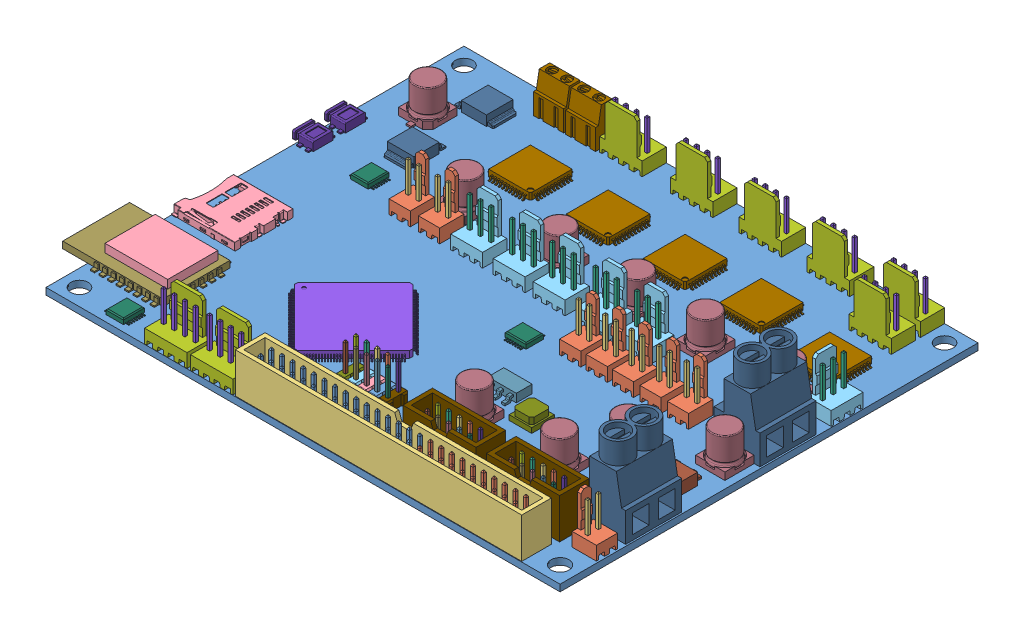
SolidWorks assembly Duet WIfi Rev 4, configuration Default. Lengths in mm.
Overall size (129 22.52 100).
221 component instances, 40 part files, 0 mates.
Components (placement in the parent):
- Main PCB v56-1: Main PCB v56 [Default] at origin size (123 1.6 100)
- Molex PCB 2 pin v2-1: Molex PCB 2 pin v2 [Default] at (-35.5344 13.1082 -6.1109) x (1 0 0) z (0 1 0) size (5.08 5.79 14.92)
  - BASE9710016_1-1: BASE9710016_1 [Default] at (2.54 2.895 -8.22) size (5.08 5.79 11.5)
  - PINO9710016_1-1: PINO9710016_1 [Default] at (1.27 3.325 -0.72) size (0.65 0.65 14.2)
  - PINO9710016_1-2: PINO9710016_1 [Default] at (3.81 3.325 -0.72) size (0.65 0.65 14.2)
- Molex PCB 2 pin v2_1-1: Molex PCB 2 pin v2_1 [Default] at (-28.4802 13.1082 -6.1109) x (1 0 0) z (0 1 0) size (5.08 5.79 14.92)
  - BASE9710016_1-1: BASE9710016_1 [Default] at (2.54 2.895 -8.22) size (5.08 5.79 11.5)
  - PINO9710016_1-1: PINO9710016_1 [Default] at (1.27 3.325 -0.72) size (0.65 0.65 14.2)
  - PINO9710016_1-2: PINO9710016_1 [Default] at (3.81 3.325 -0.72) size (0.65 0.65 14.2)
- microSD1 v4-1: microSD1 v4 [Default] at (-62.4462 1.5952 12.9853) x (0 0 1) z (-1 0 0) size (14.1 1.88 15.2)
- Molex PCB 2 pin v2_2-1: Molex PCB 2 pin v2_2 [Default] at (13.9179 13.1082 2.5426) x (1 0 0) z (0 1 0) size (5.08 5.79 14.92)
  - BASE9710016_1-1: BASE9710016_1 [Default] at (2.54 2.895 -8.22) size (5.08 5.79 11.5)
  - PINO9710016_1-1: PINO9710016_1 [Default] at (1.27 3.325 -0.72) size (0.65 0.65 14.2)
  - PINO9710016_1-2: PINO9710016_1 [Default] at (3.81 3.325 -0.72) size (0.65 0.65 14.2)
- Molex PCB 2 pin v2_3-1: Molex PCB 2 pin v2_3 [Default] at (20.2886 13.1082 2.5426) x (1 0 0) z (0 1 0) size (5.08 5.79 14.92)
  - BASE9710016_1-1: BASE9710016_1 [Default] at (2.54 2.895 -8.22) size (5.08 5.79 11.5)
  - PINO9710016_1-1: PINO9710016_1 [Default] at (1.27 3.325 -0.72) size (0.65 0.65 14.2)
  - PINO9710016_1-2: PINO9710016_1 [Default] at (3.81 3.325 -0.72) size (0.65 0.65 14.2)
- Molex PCB 2 pin v2_4-1: Molex PCB 2 pin v2_4 [Default] at (26.5531 13.1082 2.5426) x (1 0 0) z (0 1 0) size (5.08 5.79 14.92)
  - BASE9710016_1-1: BASE9710016_1 [Default] at (2.54 2.895 -8.22) size (5.08 5.79 11.5)
  - PINO9710016_1-1: PINO9710016_1 [Default] at (1.27 3.325 -0.72) size (0.65 0.65 14.2)
  - PINO9710016_1-2: PINO9710016_1 [Default] at (3.81 3.325 -0.72) size (0.65 0.65 14.2)
- Molex PCB 2 pin v2_5-1: Molex PCB 2 pin v2_5 [Default] at (33.1361 13.1082 2.5426) x (1 0 0) z (0 1 0) size (5.08 5.79 14.92)
  - BASE9710016_1-1: BASE9710016_1 [Default] at (2.54 2.895 -8.22) size (5.08 5.79 11.5)
  - PINO9710016_1-1: PINO9710016_1 [Default] at (1.27 3.325 -0.72) size (0.65 0.65 14.2)
  - PINO9710016_1-2: PINO9710016_1 [Default] at (3.81 3.325 -0.72) size (0.65 0.65 14.2)
- Molex PCB 2 pin v2_6-1: Molex PCB 2 pin v2_6 [Default] at (39.7191 13.1082 2.5426) x (1 0 0) z (0 1 0) size (5.08 5.79 14.92)
  - BASE9710016_1-1: BASE9710016_1 [Default] at (2.54 2.895 -8.22) size (5.08 5.79 11.5)
  - PINO9710016_1-1: PINO9710016_1 [Default] at (1.27 3.325 -0.72) size (0.65 0.65 14.2)
  - PINO9710016_1-2: PINO9710016_1 [Default] at (3.81 3.325 -0.72) size (0.65 0.65 14.2)
- Molex PCB 3 pin v2 v6-1: Molex PCB 3 pin v2 v6 [Default] at (-20.7566 13.2093 -6.0914) x (1 0 0) z (0 1 0) size (7.62 5.79 14.92)
  - BASE9710016_2-1: BASE9710016_2 [Default] at (2.54 2.895 -8.22) size (7.62 5.79 11.5)
  - PINO9710016_2-1: PINO9710016_2 [Default] at (1.27 3.325 -0.72) size (0.65 0.65 14.2)
  - PINO9710016_2-2: PINO9710016_2 [Default] at (3.81 3.325 -0.72) size (0.65 0.65 14.2)
  - PINO9710016_2-3: PINO9710016_2 [Default] at (6.35 3.325 -0.72) size (0.65 0.65 14.2)
- Molex PCB 3 pin v2 v6_1-1: Molex PCB 3 pin v2 v6_1 [Default] at (-10.5889 13.2093 -6.0914) x (1 0 0) z (0 1 0) size (7.62 5.79 14.92)
  - BASE9710016_2-1: BASE9710016_2 [Default] at (2.54 2.895 -8.22) size (7.62 5.79 11.5)
  - PINO9710016_2-1: PINO9710016_2 [Default] at (1.27 3.325 -0.72) size (0.65 0.65 14.2)
  - PINO9710016_2-2: PINO9710016_2 [Default] at (3.81 3.325 -0.72) size (0.65 0.65 14.2)
  - PINO9710016_2-3: PINO9710016_2 [Default] at (6.35 3.325 -0.72) size (0.65 0.65 14.2)
- Molex PCB 3 pin v2 v6_2-1: Molex PCB 3 pin v2 v6_2 [Default] at (-1.0164 13.2093 -6.0914) x (1 0 0) z (0 1 0) size (7.62 5.79 14.92)
  - BASE9710016_2-1: BASE9710016_2 [Default] at (2.54 2.895 -8.22) size (7.62 5.79 11.5)
  - PINO9710016_2-1: PINO9710016_2 [Default] at (1.27 3.325 -0.72) size (0.65 0.65 14.2)
  - PINO9710016_2-2: PINO9710016_2 [Default] at (3.81 3.325 -0.72) size (0.65 0.65 14.2)
  - PINO9710016_2-3: PINO9710016_2 [Default] at (6.35 3.325 -0.72) size (0.65 0.65 14.2)
- Molex PCB 3 pin v2 v6_3-1: Molex PCB 3 pin v2 v6_3 [Default] at (9.3326 13.2093 -6.0914) x (1 0 0) z (0 1 0) size (7.62 5.79 14.92)
  - BASE9710016_2-1: BASE9710016_2 [Default] at (2.54 2.895 -8.22) size (7.62 5.79 11.5)
  - PINO9710016_2-1: PINO9710016_2 [Default] at (1.27 3.325 -0.72) size (0.65 0.65 14.2)
  - PINO9710016_2-2: PINO9710016_2 [Default] at (3.81 3.325 -0.72) size (0.65 0.65 14.2)
  - PINO9710016_2-3: PINO9710016_2 [Default] at (6.35 3.325 -0.72) size (0.65 0.65 14.2)
- Molex PCB 3 pin v2 v6_4-1: Molex PCB 3 pin v2 v6_4 [Default] at (19.2437 13.2093 -6.0914) x (1 0 0) z (0 1 0) size (7.62 5.79 14.92)
  - BASE9710016_2-1: BASE9710016_2 [Default] at (2.54 2.895 -8.22) size (7.62 5.79 11.5)
  - PINO9710016_2-1: PINO9710016_2 [Default] at (1.27 3.325 -0.72) size (0.65 0.65 14.2)
  - PINO9710016_2-2: PINO9710016_2 [Default] at (3.81 3.325 -0.72) size (0.65 0.65 14.2)
  - PINO9710016_2-3: PINO9710016_2 [Default] at (6.35 3.325 -0.72) size (0.65 0.65 14.2)
- Molex PCB 4 pin v3-1: Molex PCB 4 pin v3 [Default] at (-37.9459 13.1477 49.9775) x (1 0 0) z (0 1 0) size (10.16 5.79 14.92)
  - BASE9710016-1: BASE9710016 [Default] at (2.54 2.895 -8.22) size (10.16 5.79 11.5)
  - PINO9710016-1: PINO9710016 [Default] at (1.27 3.325 -0.72) size (0.65 0.65 14.2)
  - PINO9710016-2: PINO9710016 [Default] at (3.81 3.325 -0.72) size (0.65 0.65 14.2)
  - PINO9710016-3: PINO9710016 [Default] at (6.35 3.325 -0.72) size (0.65 0.65 14.2)
  - PINO9710016-4: PINO9710016 [Default] at (8.89 3.325 -0.72) size (0.65 0.65 14.2)
- Molex PCB 4 pin v3_1-1: Molex PCB 4 pin v3_1 [Default] at (-26.9715 13.1477 49.9775) x (1 0 0) z (0 1 0) size (10.16 5.79 14.92)
  - BASE9710016-1: BASE9710016 [Default] at (2.54 2.895 -8.22) size (10.16 5.79 11.5)
  - PINO9710016-1: PINO9710016 [Default] at (1.27 3.325 -0.72) size (0.65 0.65 14.2)
  - PINO9710016-2: PINO9710016 [Default] at (3.81 3.325 -0.72) size (0.65 0.65 14.2)
  - PINO9710016-3: PINO9710016 [Default] at (6.35 3.325 -0.72) size (0.65 0.65 14.2)
  - PINO9710016-4: PINO9710016 [Default] at (8.89 3.325 -0.72) size (0.65 0.65 14.2)
- Molex PCB 4 pin v3_2-1: Molex PCB 4 pin v3_2 [Default] at (-13.0474 13.1477 -49.9787) x (-1 0 0) z (0 1 0) size (10.16 5.79 14.92)
  - BASE9710016-1: BASE9710016 [Default] at (2.54 2.895 -8.22) size (10.16 5.79 11.5)
  - PINO9710016-1: PINO9710016 [Default] at (1.27 3.325 -0.72) size (0.65 0.65 14.2)
  - PINO9710016-2: PINO9710016 [Default] at (3.81 3.325 -0.72) size (0.65 0.65 14.2)
  - PINO9710016-3: PINO9710016 [Default] at (6.35 3.325 -0.72) size (0.65 0.65 14.2)
  - PINO9710016-4: PINO9710016 [Default] at (8.89 3.325 -0.72) size (0.65 0.65 14.2)
- Molex PCB 4 pin v3_3-1: Molex PCB 4 pin v3_3 [Default] at (3.87 13.1477 -49.9787) x (-1 0 0) z (0 1 0) size (10.16 5.79 14.92)
  - BASE9710016-1: BASE9710016 [Default] at (2.54 2.895 -8.22) size (10.16 5.79 11.5)
  - PINO9710016-1: PINO9710016 [Default] at (1.27 3.325 -0.72) size (0.65 0.65 14.2)
  - PINO9710016-2: PINO9710016 [Default] at (3.81 3.325 -0.72) size (0.65 0.65 14.2)
  - PINO9710016-3: PINO9710016 [Default] at (6.35 3.325 -0.72) size (0.65 0.65 14.2)
  - PINO9710016-4: PINO9710016 [Default] at (8.89 3.325 -0.72) size (0.65 0.65 14.2)
- Molex PCB 4 pin v3_4-1: Molex PCB 4 pin v3_4 [Default] at (20.2963 13.1477 -49.9787) x (-1 0 0) z (0 1 0) size (10.16 5.79 14.92)
  - BASE9710016-1: BASE9710016 [Default] at (2.54 2.895 -8.22) size (10.16 5.79 11.5)
  - PINO9710016-1: PINO9710016 [Default] at (1.27 3.325 -0.72) size (0.65 0.65 14.2)
  - PINO9710016-2: PINO9710016 [Default] at (3.81 3.325 -0.72) size (0.65 0.65 14.2)
  - PINO9710016-3: PINO9710016 [Default] at (6.35 3.325 -0.72) size (0.65 0.65 14.2)
  - PINO9710016-4: PINO9710016 [Default] at (8.89 3.325 -0.72) size (0.65 0.65 14.2)
- Molex PCB 4 pin v3_5-1: Molex PCB 4 pin v3_5 [Default] at (36.6134 13.1477 -49.9787) x (-1 0 0) z (0 1 0) size (10.16 5.79 14.92)
  - BASE9710016-1: BASE9710016 [Default] at (2.54 2.895 -8.22) size (10.16 5.79 11.5)
  - PINO9710016-1: PINO9710016 [Default] at (1.27 3.325 -0.72) size (0.65 0.65 14.2)
  - PINO9710016-2: PINO9710016 [Default] at (3.81 3.325 -0.72) size (0.65 0.65 14.2)
  - PINO9710016-3: PINO9710016 [Default] at (6.35 3.325 -0.72) size (0.65 0.65 14.2)
  - PINO9710016-4: PINO9710016 [Default] at (8.89 3.325 -0.72) size (0.65 0.65 14.2)
- Molex PCB 4 pin v3_6-1: Molex PCB 4 pin v3_6 [Default] at (53.5582 13.1477 -49.9787) x (-1 0 0) z (0 1 0) size (10.16 5.79 14.92)
  - BASE9710016-1: BASE9710016 [Default] at (2.54 2.895 -8.22) size (10.16 5.79 11.5)
  - PINO9710016-1: PINO9710016 [Default] at (1.27 3.325 -0.72) size (0.65 0.65 14.2)
  - PINO9710016-2: PINO9710016 [Default] at (3.81 3.325 -0.72) size (0.65 0.65 14.2)
  - PINO9710016-3: PINO9710016 [Default] at (6.35 3.325 -0.72) size (0.65 0.65 14.2)
  - PINO9710016-4: PINO9710016 [Default] at (8.89 3.325 -0.72) size (0.65 0.65 14.2)
- Molex PCB 4 pin v3_7-1: Molex PCB 4 pin v3_7 [Default] at (53.5582 13.1477 -42.9934) x (-1 0 0) z (0 1 0) size (10.16 5.79 14.92)
  - BASE9710016-1: BASE9710016 [Default] at (2.54 2.895 -8.22) size (10.16 5.79 11.5)
  - PINO9710016-1: PINO9710016 [Default] at (1.27 3.325 -0.72) size (0.65 0.65 14.2)
  - PINO9710016-2: PINO9710016 [Default] at (3.81 3.325 -0.72) size (0.65 0.65 14.2)
  - PINO9710016-3: PINO9710016 [Default] at (6.35 3.325 -0.72) size (0.65 0.65 14.2)
  - PINO9710016-4: PINO9710016 [Default] at (8.89 3.325 -0.72) size (0.65 0.65 14.2)
- 2 pole terminal block v7-1: 2 pole terminal block v7 [Default] at (-27.4689 1.6269 -46.8568) x (-1 0 0) z (0 0 -1) size (7.2 9 6)
- 2 pole terminal block v7-2: 2 pole terminal block v7 [Default] at (-35.1283 1.6572 -46.8568) x (-1 0 0) z (0 0 -1) size (7.2 9 6)
- 2 pole terminal block large v7-1: 2 pole terminal block large v7 [Default] at (55.6089 1.6 -4.9109) x (0 0 -1) z (1 0 0) size (13.4 19.1 11)
- 2 pole terminal block large v7-2: 2 pole terminal block large v7 [Default] at (55.6089 1.6 27.2029) x (0 0 -1) z (1 0 0) size (13.4 19.1 11)
- Molex PCB 2 pin v2_7-1: Molex PCB 2 pin v2_7 [Default] at (61.0807 13.1082 40.8944) x (0 0 -1) z (0 1 0) size (5.08 5.79 14.92)
  - BASE9710016_1-1: BASE9710016_1 [Default] at (2.54 2.895 -8.22) size (5.08 5.79 11.5)
  - PINO9710016_1-1: PINO9710016_1 [Default] at (1.27 3.325 -0.72) size (0.65 0.65 14.2)
  - PINO9710016_1-2: PINO9710016_1 [Default] at (3.81 3.325 -0.72) size (0.65 0.65 14.2)
- Molex PCB 3 pin v2 v6_5-1: Molex PCB 3 pin v2 v6_5 [Default] at (61.3453 13.2093 -15.0112) x (0 0 -1) z (0 1 0) size (7.62 5.79 14.92)
  - BASE9710016_2-1: BASE9710016_2 [Default] at (2.54 2.895 -8.22) size (7.62 5.79 11.5)
  - PINO9710016_2-1: PINO9710016_2 [Default] at (1.27 3.325 -0.72) size (0.65 0.65 14.2)
  - PINO9710016_2-2: PINO9710016_2 [Default] at (3.81 3.325 -0.72) size (0.65 0.65 14.2)
  - PINO9710016_2-3: PINO9710016_2 [Default] at (6.35 3.325 -0.72) size (0.65 0.65 14.2)
- Pin Header 2x5 TH Pitch 2.54mm v4-1: Pin Header 2x5 TH Pitch 2.54mm v4 [Default] at (-5.2178 1.6022 33.3605) x (1 0 0) z (0 1 0) size (12.7 5.08 12.7)
  - Component1_5-1: Component1_5 [Default] at origin size (0.63 0.63 12.7)
  - Component2-1: Component2 [Default] at origin size (0.63 0.63 12.7)
  - Component3-1: Component3 [Default] at origin size (0.63 0.63 12.7)
  - Component4-1: Component4 [Default] at origin size (0.63 0.63 12.7)
  - Component5-1: Component5 [Default] at origin size (0.63 0.63 12.7)
  - Component6-1: Component6 [Default] at origin size (2.54 5.08 2.8)
  - Component7-1: Component7 [Default] at origin size (0.63 0.63 12.7)
  - Component8-1: Component8 [Default] at origin size (2.54 5.08 2.8)
  - Component9-1: Component9 [Default] at origin size (2.54 5.08 2.8)
  - Component10-1: Component10 [Default] at origin size (0.63 0.63 12.7)
  - Component11-1: Component11 [Default] at origin size (0.63 0.63 12.7)
  - Component12-1: Component12 [Default] at origin size (2.54 5.08 2.8)
  - Component13-1: Component13 [Default] at origin size (2.54 5.08 2.8)
  - Component14-1: Component14 [Default] at origin size (0.63 0.63 12.7)
  - Component15-1: Component15 [Default] at origin size (0.63 0.63 12.7)
- Arm cortex Sam4E8E v6 v7-1: Arm cortex Sam4E8E v6 v7 [Default] at (-17.0062 1.6459 20.877) x (0.707107 0 0.707107) z (-0.707107 0 0.707107) size (22 1.6 22)
  - Component1-1: Component1 [Default] at origin size (22 1.6 22)
- Trinamic 2660-PA v3-1: Trinamic 2660-PA v3 [Default] at (-26.4607 1.6002 -30.8647) x (-1 0 -0.000001) z (0.000001 0 -1) size (12 1.6 12)
  - Component1_1-1: Component1_1 [Default] at origin size (12 1.6 12)
- Trinamic 2660-PA v3-2: Trinamic 2660-PA v3 [Default] at (-7.8607 1.6002 -30.8647) x (-1 0 -0.000001) z (0.000001 0 -1) size (12 1.6 12)
  - Component1_1-1: Component1_1 [Default] at origin size (12 1.6 12)
- Trinamic 2660-PA v3-3: Trinamic 2660-PA v3 [Default] at (10.5393 1.6002 -30.8647) x (-1 0 -0.000001) z (0.000001 0 -1) size (12 1.6 12)
  - Component1_1-1: Component1_1 [Default] at origin size (12 1.6 12)
- Trinamic 2660-PA v3-4: Trinamic 2660-PA v3 [Default] at (28.8037 1.6002 -30.8647) x (-1 0 -0.000001) z (0.000001 0 -1) size (12 1.6 12)
  - Component1_1-1: Component1_1 [Default] at origin size (12 1.6 12)
- Trinamic 2660-PA v3_1-1: Trinamic 2660-PA v3_1 [Default] at (48.089 1.6002 -27.9115) x (-1 0 -0.000001) z (0.000001 0 -1) size (12 1.6 12)
  - Component1_1-1: Component1_1 [Default] at origin size (12 1.6 12)
- MOSFET v9-1: MOSFET v9 [Default] at (-45.1235 1.6199 -39.2021) x (0 0 1) z (-1 0 0) size (6.4 2.4 9.33)
- MOSFET v9-2: MOSFET v9 [Default] at (-45.3181 1.6199 -21.674) x (-1 0 0) z (0 0 -1) size (6.4 2.4 9.33)
- Power reg v5-1: Power reg v5 [Default] at (54.1912 1.6402 16.2036) x (-1 0 0) z (0 0 -1) size (6.8 2.8 9.2)
- Duet Wifi daughter board  v25-1: Duet Wifi daughter board  v25 [Default] at (-55.2292 8.9057 28.17) size (25 1.6 18.4)
  - Component1_2-1: Component1_2 [Default] at (-0.2708 -7.3057 3.83) size (25 1.6 18.4)
- PCB 7mm cap v8-1: PCB 7mm cap v8 [Default] at (-5.0295 1.5787 -16.3984) size (7 8 8.14)
  - Component1_3-1: Component1_3 [Default] at origin size (7 8 8.14)
- PCB 7mm cap v8_1-1: PCB 7mm cap v8_1 [Default] at (-27.7717 1.5787 -16.5362) size (7 8 8.14)
  - Component1_3-1: Component1_3 [Default] at origin size (7 8 8.14)
- PCB 7mm cap v8_2-1: PCB 7mm cap v8_2 [Default] at (13.3988 1.5787 -16.4775) size (7 8 8.14)
  - Component1_3-1: Component1_3 [Default] at origin size (7 8 8.14)
- PCB 7mm cap v8_3-1: PCB 7mm cap v8_3 [Default] at (29.911 1.5787 -16.3984) size (7 8 8.14)
  - Component1_3-1: Component1_3 [Default] at origin size (7 8 8.14)
- PCB 7mm cap v8_4-1: PCB 7mm cap v8_4 [Default] at (49.8005 1.5787 -16.1299) x (-0.000012 0 -1) z (1 0 -0.000012) size (7 8 8.14)
  - Component1_3-1: Component1_3 [Default] at origin size (7 8 8.14)
- PCB 7mm cap v8_5-1: PCB 7mm cap v8_5 [Default] at (42.4342 1.5787 14.6374) x (0 0 1) z (-1 0 0) size (7 8 8.14)
  - Component1_3-1: Component1_3 [Default] at origin size (7 8 8.14)
- PCB 7mm cap v8_6-1: PCB 7mm cap v8_6 [Default] at (56.2359 1.5787 5.2974) size (7 8 8.14)
  - Component1_3-1: Component1_3 [Default] at origin size (7 8 8.14)
- PCB 7mm cap v8_7-1: PCB 7mm cap v8_7 [Default] at (37.0801 1.5787 25.7026) x (0 0 -1) z (1 0 0) size (7 8 8.14)
  - Component1_3-1: Component1_3 [Default] at origin size (7 8 8.14)
- PCB 7mm cap v8_8-1: PCB 7mm cap v8_8 [Default] at (16.7939 1.5787 25.7621) x (-1 0 0) z (0 0 -1) size (7 8 8.14)
  - Component1_3-1: Component1_3 [Default] at origin size (7 8 8.14)
- PCB 7mm cap v8_9-1: PCB 7mm cap v8_9 [Default] at (-51.4074 1.5787 -31.2726) x (-1 0 0) z (0 0 -1) size (7 8 8.14)
  - Component1_3-1: Component1_3 [Default] at origin size (7 8 8.14)
- Power reg R2 v4-1: Power reg R2 v4 [Default] at (15.3184 1.6131 15.7902) size (6.8 2 7)
- Micro P v5-1: Micro P v5 [Default] at (6.2858 1.6187 3.3147) size (5 1.2 5.8)
  - Component1_4-1: Component1_4 [Default] at origin size (5 1.2 5.8)
- Micro P v5-2: Micro P v5 [Default] at (-46.5775 1.6187 45.9806) x (0 0 -1) z (1 0 0) size (5 1.2 5.8)
  - Component1_4-1: Component1_4 [Default] at origin size (5 1.2 5.8)
- Micro P v5-3: Micro P v5 [Default] at (-45.3709 1.6187 -11.358) x (0 0 -1) z (1 0 0) size (5 1.2 5.8)
  - Component1_4-1: Component1_4 [Default] at origin size (5 1.2 5.8)
- choke v6-1: choke v6 [Default] at (24.2066 1.6283 19.4931) size (5.4 2.7 5.4)
- button switch v9-1: button switch v9 [Default] at (-59.392 1.6111 -12.4706) size (5 2 6.4)
- button switch v9-2: button switch v9 [Default] at (-59.362 1.6111 -20.1424) size (5 2 6.4)
- Pin Header 2x5 TH Pitch 2.54mm v4_1-1: Pin Header 2x5 TH Pitch 2.54mm v4_1 [Default] at (18.7961 1.6 37.7617) x (1 0 0) z (0 1 0) size (12.7 5.08 12.7)
  - Component1_5-1: Component1_5 [Default] at origin size (0.63 0.63 12.7)
  - Component2-1: Component2 [Default] at origin size (0.63 0.63 12.7)
  - Component3-1: Component3 [Default] at origin size (0.63 0.63 12.7)
  - Component4-1: Component4 [Default] at origin size (0.63 0.63 12.7)
  - Component5-1: Component5 [Default] at origin size (0.63 0.63 12.7)
  - Component6-1: Component6 [Default] at origin size (2.54 5.08 2.8)
  - Component7-1: Component7 [Default] at origin size (0.63 0.63 12.7)
  - Component8-1: Component8 [Default] at origin size (2.54 5.08 2.8)
  - Component9-1: Component9 [Default] at origin size (2.54 5.08 2.8)
  - Component10-1: Component10 [Default] at origin size (0.63 0.63 12.7)
  - Component11-1: Component11 [Default] at origin size (0.63 0.63 12.7)
  - Component12-1: Component12 [Default] at origin size (2.54 5.08 2.8)
  - Component13-1: Component13 [Default] at origin size (2.54 5.08 2.8)
  - Component14-1: Component14 [Default] at origin size (0.63 0.63 12.7)
  - Component15-1: Component15 [Default] at origin size (0.63 0.63 12.7)
- Pin Header 2x5 TH Pitch 2.54mm v4_2-1: Pin Header 2x5 TH Pitch 2.54mm v4_2 [Default] at (38.8572 1.6 37.7617) x (1 0 0) z (0 1 0) size (12.7 5.08 12.7)
  - Component1_5-1: Component1_5 [Default] at origin size (0.63 0.63 12.7)
  - Component2-1: Component2 [Default] at origin size (0.63 0.63 12.7)
  - Component3-1: Component3 [Default] at origin size (0.63 0.63 12.7)
  - Component4-1: Component4 [Default] at origin size (0.63 0.63 12.7)
  - Component5-1: Component5 [Default] at origin size (0.63 0.63 12.7)
  - Component6-1: Component6 [Default] at origin size (2.54 5.08 2.8)
  - Component7-1: Component7 [Default] at origin size (0.63 0.63 12.7)
  - Component8-1: Component8 [Default] at origin size (2.54 5.08 2.8)
  - Component9-1: Component9 [Default] at origin size (2.54 5.08 2.8)
  - Component10-1: Component10 [Default] at origin size (0.63 0.63 12.7)
  - Component11-1: Component11 [Default] at origin size (0.63 0.63 12.7)
  - Component12-1: Component12 [Default] at origin size (2.54 5.08 2.8)
  - Component13-1: Component13 [Default] at origin size (2.54 5.08 2.8)
  - Component14-1: Component14 [Default] at origin size (0.63 0.63 12.7)
  - Component15-1: Component15 [Default] at origin size (0.63 0.63 12.7)
- 2X5Pin case v6-1: 2X5Pin case v6 [Default] at (17.4643 1.6 37.7689) x (1 0 0) z (0 1 0) size (17.5 7.08 9.6)
  - Component1_6-1: Component1_6 [Default] at origin size (17.5 7.08 9.6)
- 2X5Pin case v6_1-1: 2X5Pin case v6_1 [Default] at (37.4629 1.6 37.7689) x (1 0 0) z (0 1 0) size (17.5 7.08 9.6)
  - Component1_6-1: Component1_6 [Default] at origin size (17.5 7.08 9.6)
- 25 pin with case v2-1: 25 pin with case v2 [Default] at (-12.4721 1.5997 44.5087) size (68.5 12.8 7.08)
  - Pin Header 2x15 TH Pitch 2.54mm v2-1: Pin Header 2x15 TH Pitch 2.54mm v2 [Default] at (0 0.0647 1.8778) x (1 0 0) z (0 1 0) size (38.1 5.08 12.7)
  - Pin Header 2x10 TH Pitch 2.54mm v2-1: Pin Header 2x10 TH Pitch 2.54mm v2 [Default] at (38.1 0.0647 1.8778) x (1 0 0) z (0 1 0) size (25.4 5.08 12.7)
  - 2X25Pin case v7-1: 2X25Pin case v7 [Default] x (1 0 0) z (0 1 0) size (68.5 7.08 9.6)
    - Component1_7-1: Component1_7 [Default] at (-1.5 -1.8778 0.0661) size (68.5 7.08 9.6)
- wifi chip v3-1: wifi chip v3 [Default] at (-52.469 3.2167 31.4135) x (1 0 0) z (0 1 0) size (15 12 2)
